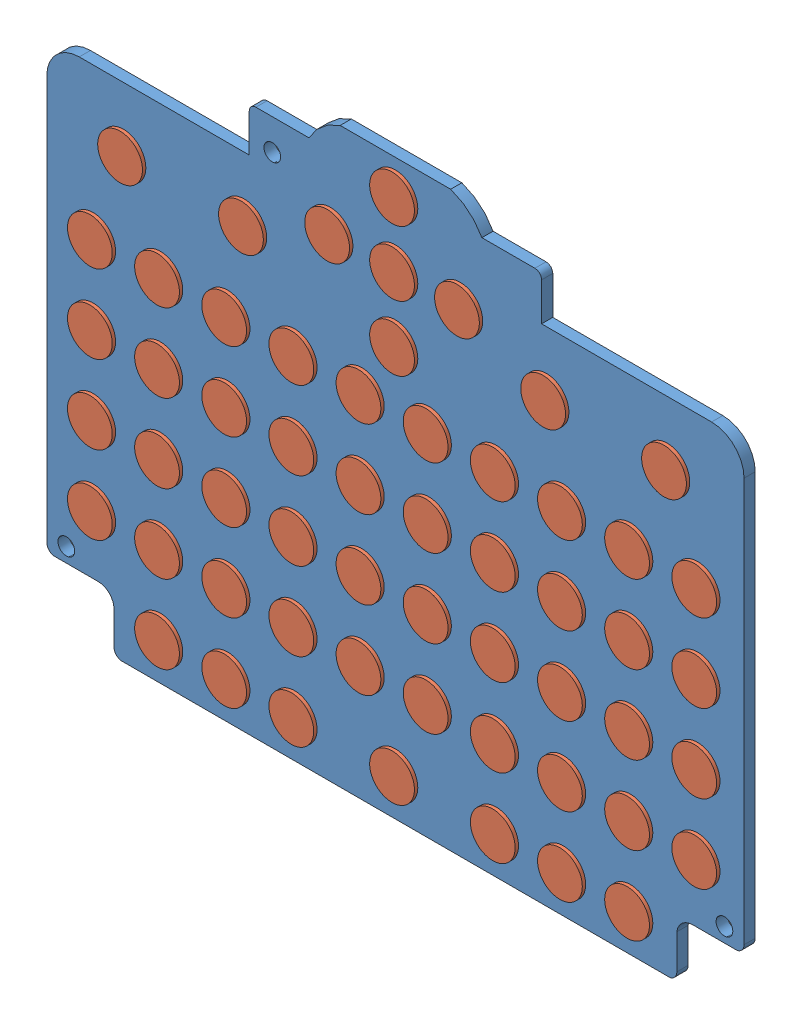
SolidWorks assembly bt-kbd-v3a, configuration Default. Lengths in mm.
Overall size (62.3 51.2 4.19).
174 component instances, 3 part files, 0 mates.
Components (placement in the parent):
- bt-kbd-v3a.step-1: bt-kbd-v3a.step [Default] at origin size (62.3 51.2 4.19)
  - Boardbt-kbd-v3a.step-1: Boardbt-kbd-v3a.step [Default] at origin size (62.3 51.2 1)
    - Open CASCADE STEP translator 6.8 1.1.1.step-1: Open CASCADE STEP translator 6.8 1.1.1.step [Default] at (0 0 -1) size (62.3 51.2 1)
  - P26bt-kbd-v3a.step-1: P26bt-kbd-v3a.step [Default] at origin size (4 4 0.3)
    - 6717928320.step-1: 6717928320.step [Default] at (-9.0001 -40.9701 0) size (4 4 0.3)
      - Cylinder.step-1: Cylinder.step [Default] at origin size (4 4 0.3)
  - PCbt-kbd-v3a.step-1: PCbt-kbd-v3a.step [Default] at origin size (4 4 0.3)
    - 6717928320.step-1: 6717928320.step [Default] at (-0.0001 -22.9701 0) size (4 4 0.3)
      - Cylinder.step-1: Cylinder.step [Default] at origin size (4 4 0.3)
  - P55Bbt-kbd-v3a.step-1: P55Bbt-kbd-v3a.step [Default] at origin size (4 4 0.3)
    - 6717928320.step-1: 6717928320.step [Default] at (-9.0001 -61.9701 0) size (4 4 0.3)
      - Cylinder.step-1: Cylinder.step [Default] at origin size (4 4 0.3)
  - P55Abt-kbd-v3a.step-1: P55Abt-kbd-v3a.step [Default] at origin size (4 4 0.3)
    - 6717928320.step-1: 6717928320.step [Default] at (8.9999 -61.9701 0) size (4 4 0.3)
      - Cylinder.step-1: Cylinder.step [Default] at origin size (4 4 0.3)
  - P9bt-kbd-v3a.step-1: P9bt-kbd-v3a.step [Default] at origin size (4 4 0.3)
    - 6717928320.step-1: 6717928320.step [Default] at (-0.0001 -28.7701 0) size (4 4 0.3)
      - Cylinder.step-1: Cylinder.step [Default] at origin size (4 4 0.3)
  - P8bt-kbd-v3a.step-1: P8bt-kbd-v3a.step [Default] at origin size (4 4 0.3)
    - 6717928320.step-1: 6717928320.step [Default] at (24.2999 -26.1701 0) size (4 4 0.3)
      - Cylinder.step-1: Cylinder.step [Default] at origin size (4 4 0.3)
  - P7bt-kbd-v3a.step-1: P7bt-kbd-v3a.step [Default] at origin size (4 4 0.3)
    - 6717928320.step-1: 6717928320.step [Default] at (13.4999 -26.1701 0) size (4 4 0.3)
      - Cylinder.step-1: Cylinder.step [Default] at origin size (4 4 0.3)
  - P6bt-kbd-v3a.step-1: P6bt-kbd-v3a.step [Default] at origin size (4 4 0.3)
    - 6717928320.step-1: 6717928320.step [Default] at (5.7999 -22.9701 0) size (4 4 0.3)
      - Cylinder.step-1: Cylinder.step [Default] at origin size (4 4 0.3)
  - P5bt-kbd-v3a.step-1: P5bt-kbd-v3a.step [Default] at origin size (4 4 0.3)
    - 6717928320.step-1: 6717928320.step [Default] at (-5.8001 -22.9701 0) size (4 4 0.3)
      - Cylinder.step-1: Cylinder.step [Default] at origin size (4 4 0.3)
  - P4bt-kbd-v3a.step-1: P4bt-kbd-v3a.step [Default] at origin size (4 4 0.3)
    - 6717928320.step-1: 6717928320.step [Default] at (-13.5001 -26.1701 0) size (4 4 0.3)
      - Cylinder.step-1: Cylinder.step [Default] at origin size (4 4 0.3)
  - P3bt-kbd-v3a.step-1: P3bt-kbd-v3a.step [Default] at origin size (4 4 0.3)
    - 6717928320.step-1: 6717928320.step [Default] at (-24.3001 -26.1701 0) size (4 4 0.3)
      - Cylinder.step-1: Cylinder.step [Default] at origin size (4 4 0.3)
  - P2bt-kbd-v3a.step-1: P2bt-kbd-v3a.step [Default] at origin size (4 4 0.3)
    - 6717928320.step-1: 6717928320.step [Default] at (-0.0001 -17.1701 0) size (4 4 0.3)
      - Cylinder.step-1: Cylinder.step [Default] at origin size (4 4 0.3)
  - P1bt-kbd-v3a.step-1: P1bt-kbd-v3a.step [Default] at origin size (3.38 8.6 2.9)
    - DF40HC(3.0)-30DS.step-1: DF40HC(3.0)-30DS.step [Default] at (-19.4957 -36.1172 -2.49) x (-1 0 0) z (0 -1 0) size (3.38 2.9 8.6)
      - DF40HC(3.0)-30DS-0.step-1: DF40HC(3.0)-30DS-0.step [Default] at (0 -0.5 7.77) x (-1 0 0) z (0 0 1) size (3.38 2.9 8.6)
  - P13bt-kbd-v3a.step-1: P13bt-kbd-v3a.step [Default] at origin size (4 4 0.3)
    - 6717928320.step-1: 6717928320.step [Default] at (-27.0001 -33.9701 0) size (4 4 0.3)
      - Cylinder.step-1: Cylinder.step [Default] at origin size (4 4 0.3)
  - P14bt-kbd-v3a.step-1: P14bt-kbd-v3a.step [Default] at origin size (4 4 0.3)
    - 6717928320.step-1: 6717928320.step [Default] at (-21.0001 -33.9701 0) size (4 4 0.3)
      - Cylinder.step-1: Cylinder.step [Default] at origin size (4 4 0.3)
  - P15bt-kbd-v3a.step-1: P15bt-kbd-v3a.step [Default] at origin size (4 4 0.3)
    - 6717928320.step-1: 6717928320.step [Default] at (-15.0001 -33.9701 0) size (4 4 0.3)
      - Cylinder.step-1: Cylinder.step [Default] at origin size (4 4 0.3)
  - P16bt-kbd-v3a.step-1: P16bt-kbd-v3a.step [Default] at origin size (4 4 0.3)
    - 6717928320.step-1: 6717928320.step [Default] at (-9.0001 -33.9701 0) size (4 4 0.3)
      - Cylinder.step-1: Cylinder.step [Default] at origin size (4 4 0.3)
  - P17bt-kbd-v3a.step-1: P17bt-kbd-v3a.step [Default] at origin size (4 4 0.3)
    - 6717928320.step-1: 6717928320.step [Default] at (-3.0001 -33.9701 0) size (4 4 0.3)
      - Cylinder.step-1: Cylinder.step [Default] at origin size (4 4 0.3)
  - P18bt-kbd-v3a.step-1: P18bt-kbd-v3a.step [Default] at origin size (4 4 0.3)
    - 6717928320.step-1: 6717928320.step [Default] at (2.9999 -33.9701 0) size (4 4 0.3)
      - Cylinder.step-1: Cylinder.step [Default] at origin size (4 4 0.3)
  - P19bt-kbd-v3a.step-1: P19bt-kbd-v3a.step [Default] at origin size (4 4 0.3)
    - 6717928320.step-1: 6717928320.step [Default] at (8.9999 -33.9701 0) size (4 4 0.3)
      - Cylinder.step-1: Cylinder.step [Default] at origin size (4 4 0.3)
  - P20bt-kbd-v3a.step-1: P20bt-kbd-v3a.step [Default] at origin size (4 4 0.3)
    - 6717928320.step-1: 6717928320.step [Default] at (14.9999 -33.9701 0) size (4 4 0.3)
      - Cylinder.step-1: Cylinder.step [Default] at origin size (4 4 0.3)
  - P21bt-kbd-v3a.step-1: P21bt-kbd-v3a.step [Default] at origin size (4 4 0.3)
    - 6717928320.step-1: 6717928320.step [Default] at (20.9999 -33.9701 0) size (4 4 0.3)
      - Cylinder.step-1: Cylinder.step [Default] at origin size (4 4 0.3)
  - P22bt-kbd-v3a.step-1: P22bt-kbd-v3a.step [Default] at origin size (4 4 0.3)
    - 6717928320.step-1: 6717928320.step [Default] at (26.9999 -33.9701 0) size (4 4 0.3)
      - Cylinder.step-1: Cylinder.step [Default] at origin size (4 4 0.3)
  - P23bt-kbd-v3a.step-1: P23bt-kbd-v3a.step [Default] at origin size (4 4 0.3)
    - 6717928320.step-1: 6717928320.step [Default] at (-27.0001 -40.9701 0) size (4 4 0.3)
      - Cylinder.step-1: Cylinder.step [Default] at origin size (4 4 0.3)
  - P24bt-kbd-v3a.step-1: P24bt-kbd-v3a.step [Default] at origin size (4 4 0.3)
    - 6717928320.step-1: 6717928320.step [Default] at (-21.0001 -40.9701 0) size (4 4 0.3)
      - Cylinder.step-1: Cylinder.step [Default] at origin size (4 4 0.3)
  - P25bt-kbd-v3a.step-1: P25bt-kbd-v3a.step [Default] at origin size (4 4 0.3)
    - 6717928320.step-1: 6717928320.step [Default] at (-15.0001 -40.9701 0) size (4 4 0.3)
      - Cylinder.step-1: Cylinder.step [Default] at origin size (4 4 0.3)
  - P27bt-kbd-v3a.step-1: P27bt-kbd-v3a.step [Default] at origin size (4 4 0.3)
    - 6717928320.step-1: 6717928320.step [Default] at (-3.0001 -40.9701 0) size (4 4 0.3)
      - Cylinder.step-1: Cylinder.step [Default] at origin size (4 4 0.3)
  - P28bt-kbd-v3a.step-1: P28bt-kbd-v3a.step [Default] at origin size (4 4 0.3)
    - 6717928320.step-1: 6717928320.step [Default] at (2.9999 -40.9701 0) size (4 4 0.3)
      - Cylinder.step-1: Cylinder.step [Default] at origin size (4 4 0.3)
  - P29bt-kbd-v3a.step-1: P29bt-kbd-v3a.step [Default] at origin size (4 4 0.3)
    - 6717928320.step-1: 6717928320.step [Default] at (8.9999 -40.9701 0) size (4 4 0.3)
      - Cylinder.step-1: Cylinder.step [Default] at origin size (4 4 0.3)
  - P30bt-kbd-v3a.step-1: P30bt-kbd-v3a.step [Default] at origin size (4 4 0.3)
    - 6717928320.step-1: 6717928320.step [Default] at (14.9999 -40.9701 0) size (4 4 0.3)
      - Cylinder.step-1: Cylinder.step [Default] at origin size (4 4 0.3)
  - P31bt-kbd-v3a.step-1: P31bt-kbd-v3a.step [Default] at origin size (4 4 0.3)
    - 6717928320.step-1: 6717928320.step [Default] at (20.9999 -40.9701 0) size (4 4 0.3)
      - Cylinder.step-1: Cylinder.step [Default] at origin size (4 4 0.3)
  - P32bt-kbd-v3a.step-1: P32bt-kbd-v3a.step [Default] at origin size (4 4 0.3)
    - 6717928320.step-1: 6717928320.step [Default] at (26.9999 -40.9701 0) size (4 4 0.3)
      - Cylinder.step-1: Cylinder.step [Default] at origin size (4 4 0.3)
  - P33bt-kbd-v3a.step-1: P33bt-kbd-v3a.step [Default] at origin size (4 4 0.3)
    - 6717928320.step-1: 6717928320.step [Default] at (-27.0001 -47.9701 0) size (4 4 0.3)
      - Cylinder.step-1: Cylinder.step [Default] at origin size (4 4 0.3)
  - P34bt-kbd-v3a.step-1: P34bt-kbd-v3a.step [Default] at origin size (4 4 0.3)
    - 6717928320.step-1: 6717928320.step [Default] at (-21.0001 -47.9701 0) size (4 4 0.3)
      - Cylinder.step-1: Cylinder.step [Default] at origin size (4 4 0.3)
  - P35bt-kbd-v3a.step-1: P35bt-kbd-v3a.step [Default] at origin size (4 4 0.3)
    - 6717928320.step-1: 6717928320.step [Default] at (-15.0001 -47.9701 0) size (4 4 0.3)
      - Cylinder.step-1: Cylinder.step [Default] at origin size (4 4 0.3)
  - P36bt-kbd-v3a.step-1: P36bt-kbd-v3a.step [Default] at origin size (4 4 0.3)
    - 6717928320.step-1: 6717928320.step [Default] at (-9.0001 -47.9701 0) size (4 4 0.3)
      - Cylinder.step-1: Cylinder.step [Default] at origin size (4 4 0.3)
  - P37bt-kbd-v3a.step-1: P37bt-kbd-v3a.step [Default] at origin size (4 4 0.3)
    - 6717928320.step-1: 6717928320.step [Default] at (-3.0001 -47.9701 0) size (4 4 0.3)
      - Cylinder.step-1: Cylinder.step [Default] at origin size (4 4 0.3)
  - P38bt-kbd-v3a.step-1: P38bt-kbd-v3a.step [Default] at origin size (4 4 0.3)
    - 6717928320.step-1: 6717928320.step [Default] at (2.9999 -47.9701 0) size (4 4 0.3)
      - Cylinder.step-1: Cylinder.step [Default] at origin size (4 4 0.3)
  - P39bt-kbd-v3a.step-1: P39bt-kbd-v3a.step [Default] at origin size (4 4 0.3)
    - 6717928320.step-1: 6717928320.step [Default] at (8.9999 -47.9701 0) size (4 4 0.3)
      - Cylinder.step-1: Cylinder.step [Default] at origin size (4 4 0.3)
  - P40bt-kbd-v3a.step-1: P40bt-kbd-v3a.step [Default] at origin size (4 4 0.3)
    - 6717928320.step-1: 6717928320.step [Default] at (14.9999 -47.9701 0) size (4 4 0.3)
      - Cylinder.step-1: Cylinder.step [Default] at origin size (4 4 0.3)
  - P41bt-kbd-v3a.step-1: P41bt-kbd-v3a.step [Default] at origin size (4 4 0.3)
    - 6717928320.step-1: 6717928320.step [Default] at (20.9999 -47.9701 0) size (4 4 0.3)
      - Cylinder.step-1: Cylinder.step [Default] at origin size (4 4 0.3)
  - P42bt-kbd-v3a.step-1: P42bt-kbd-v3a.step [Default] at origin size (4 4 0.3)
    - 6717928320.step-1: 6717928320.step [Default] at (26.9999 -47.9701 0) size (4 4 0.3)
      - Cylinder.step-1: Cylinder.step [Default] at origin size (4 4 0.3)
  - P43bt-kbd-v3a.step-1: P43bt-kbd-v3a.step [Default] at origin size (4 4 0.3)
    - 6717928320.step-1: 6717928320.step [Default] at (-27.0001 -54.9701 0) size (4 4 0.3)
      - Cylinder.step-1: Cylinder.step [Default] at origin size (4 4 0.3)
  - P44bt-kbd-v3a.step-1: P44bt-kbd-v3a.step [Default] at origin size (4 4 0.3)
    - 6717928320.step-1: 6717928320.step [Default] at (-21.0001 -54.9701 0) size (4 4 0.3)
      - Cylinder.step-1: Cylinder.step [Default] at origin size (4 4 0.3)
  - P45bt-kbd-v3a.step-1: P45bt-kbd-v3a.step [Default] at origin size (4 4 0.3)
    - 6717928320.step-1: 6717928320.step [Default] at (-15.0001 -54.9701 0) size (4 4 0.3)
      - Cylinder.step-1: Cylinder.step [Default] at origin size (4 4 0.3)
  - P46bt-kbd-v3a.step-1: P46bt-kbd-v3a.step [Default] at origin size (4 4 0.3)
    - 6717928320.step-1: 6717928320.step [Default] at (-9.0001 -54.9701 0) size (4 4 0.3)
      - Cylinder.step-1: Cylinder.step [Default] at origin size (4 4 0.3)
  - P47bt-kbd-v3a.step-1: P47bt-kbd-v3a.step [Default] at origin size (4 4 0.3)
    - 6717928320.step-1: 6717928320.step [Default] at (-3.0001 -54.9701 0) size (4 4 0.3)
      - Cylinder.step-1: Cylinder.step [Default] at origin size (4 4 0.3)
  - P48bt-kbd-v3a.step-1: P48bt-kbd-v3a.step [Default] at origin size (4 4 0.3)
    - 6717928320.step-1: 6717928320.step [Default] at (2.9999 -54.9701 0) size (4 4 0.3)
      - Cylinder.step-1: Cylinder.step [Default] at origin size (4 4 0.3)
  - P49bt-kbd-v3a.step-1: P49bt-kbd-v3a.step [Default] at origin size (4 4 0.3)
    - 6717928320.step-1: 6717928320.step [Default] at (8.9999 -54.9701 0) size (4 4 0.3)
      - Cylinder.step-1: Cylinder.step [Default] at origin size (4 4 0.3)
  - P50bt-kbd-v3a.step-1: P50bt-kbd-v3a.step [Default] at origin size (4 4 0.3)
    - 6717928320.step-1: 6717928320.step [Default] at (14.9999 -54.9701 0) size (4 4 0.3)
      - Cylinder.step-1: Cylinder.step [Default] at origin size (4 4 0.3)
  - P51bt-kbd-v3a.step-1: P51bt-kbd-v3a.step [Default] at origin size (4 4 0.3)
    - 6717928320.step-1: 6717928320.step [Default] at (20.9999 -54.9701 0) size (4 4 0.3)
      - Cylinder.step-1: Cylinder.step [Default] at origin size (4 4 0.3)
  - P52bt-kbd-v3a.step-1: P52bt-kbd-v3a.step [Default] at origin size (4 4 0.3)
    - 6717928320.step-1: 6717928320.step [Default] at (26.9999 -54.9701 0) size (4 4 0.3)
      - Cylinder.step-1: Cylinder.step [Default] at origin size (4 4 0.3)
  - P53bt-kbd-v3a.step-1: P53bt-kbd-v3a.step [Default] at origin size (4 4 0.3)
    - 6717928320.step-1: 6717928320.step [Default] at (-21.0001 -61.9701 0) size (4 4 0.3)
      - Cylinder.step-1: Cylinder.step [Default] at origin size (4 4 0.3)
  - P54bt-kbd-v3a.step-1: P54bt-kbd-v3a.step [Default] at origin size (4 4 0.3)
    - 6717928320.step-1: 6717928320.step [Default] at (-15.0001 -61.9701 0) size (4 4 0.3)
      - Cylinder.step-1: Cylinder.step [Default] at origin size (4 4 0.3)
  - P55bt-kbd-v3a.step-1: P55bt-kbd-v3a.step [Default] at origin size (4 4 0.3)
    - 6717928320.step-1: 6717928320.step [Default] at (-0.0001 -61.9701 0) size (4 4 0.3)
      - Cylinder.step-1: Cylinder.step [Default] at origin size (4 4 0.3)
  - P56bt-kbd-v3a.step-1: P56bt-kbd-v3a.step [Default] at origin size (4 4 0.3)
    - 6717928320.step-1: 6717928320.step [Default] at (14.9999 -61.9701 0) size (4 4 0.3)
      - Cylinder.step-1: Cylinder.step [Default] at origin size (4 4 0.3)
  - P57bt-kbd-v3a.step-1: P57bt-kbd-v3a.step [Default] at origin size (4 4 0.3)
    - 6717928320.step-1: 6717928320.step [Default] at (20.9999 -61.9701 0) size (4 4 0.3)
      - Cylinder.step-1: Cylinder.step [Default] at origin size (4 4 0.3)
